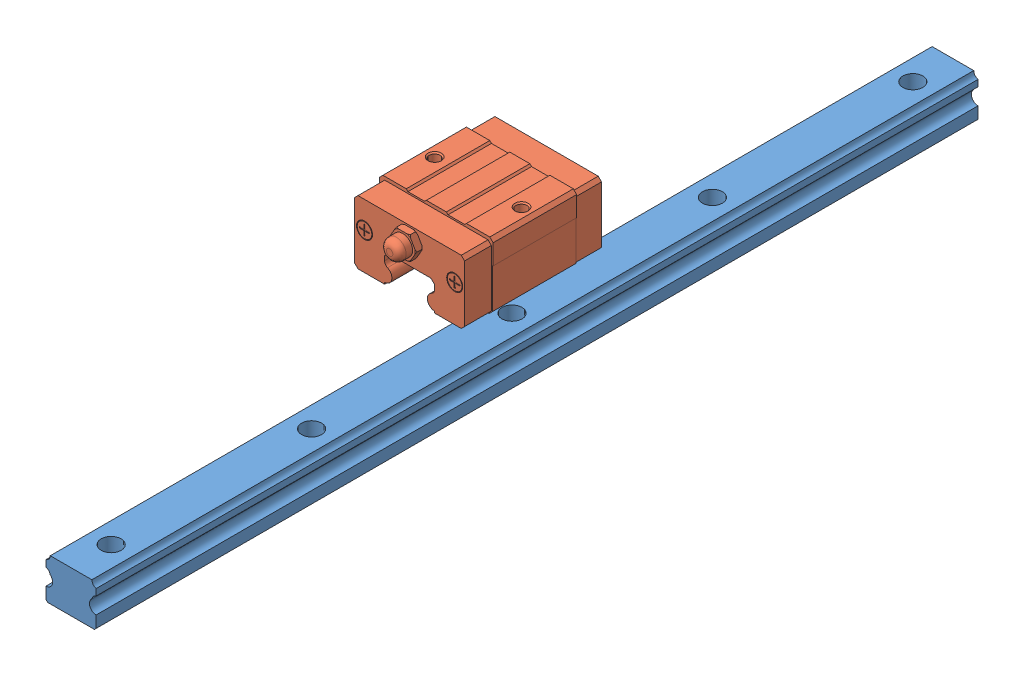
SolidWorks assembly ssvrl24_264_2_14b, configuration Standard. Lengths in mm.
Overall size (34 46.72 264).
2 component instances, 2 part files, 0 mates.
Components (placement in the parent):
- 1.1.1.1-1: 1.1.1.1 [Standard] at origin size (15 12.5 264)
- 2.1.1.1-1: 2.1.1.1 [Standard] at (-4.85 22.723 5.2992) size (34 20 47)
